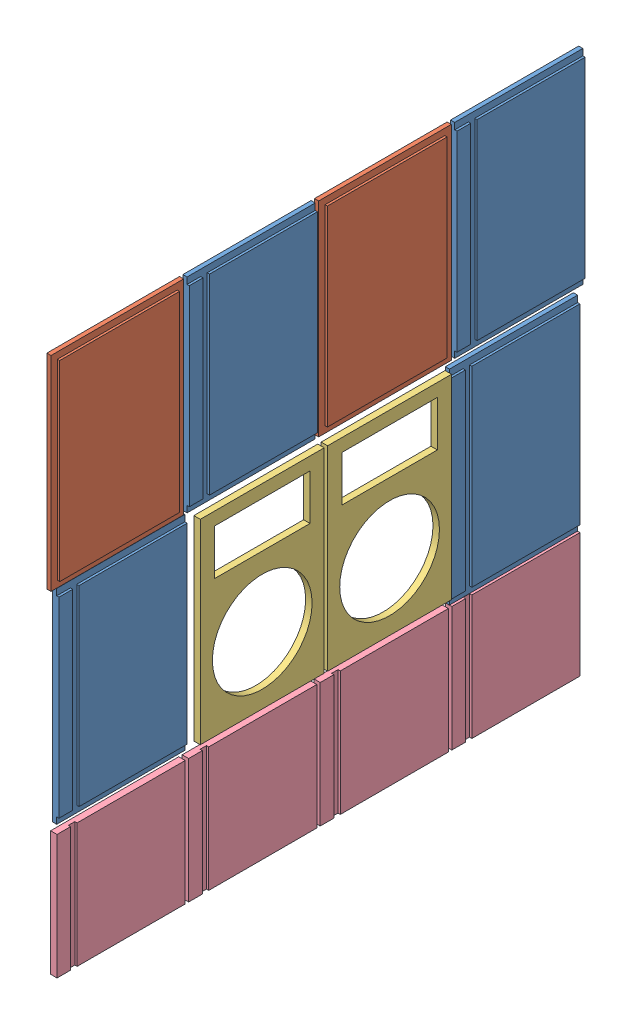
SolidWorks assembly 5x5sheet, configuration Default. Lengths in mm.
Overall size (45 1505.75 1483.58).
12 component instances, 4 part files, 29 mates.
Components (placement in the parent):
- side-1: side [Default] at (-587.3677 340.2677 830.6585) size (18 570 357.5)
- side-2: side [Default] at (-587.3677 340.2677 1577.2085) size (18 570 357.5)
- back-1: back [Default] at (-587.3677 340.2677 1210.1835) x (0 0 -1) z (1 0 0) size (370 570 18)
- Baffle-1: Baffle [Default] at (-551.3677 -213.8573 863.8532) x (0 0 1) z (-1 0 0) size (345.7 544.6 18)
- top_bottom-1: top_bottom [Default] at (-587.3677 -248.7823 1588.7649) x (0 -1 0) z (0 0 1) size (346.7 18 357.5)
- top_bottom-2: top_bottom [Default] at (-587.3677 -248.7823 487.6899) x (0 -1 0) z (0 0 1) size (346.7 18 357.5)
- back-2: back [Default] at (-587.3677 340.2677 1956.7335) x (0 0 -1) z (1 0 0) size (370 570 18)
- Baffle-2: Baffle [Default] at (-569.3677 -213.8573 1564.7782) x (0 0 -1) z (1 0 0) size (345.7 544.6 18)
- side-3: side [Default] at (-596.3677 -239.2573 1931.8032) size (18 570 357.5)
- side-4: side [Default] at (-578.3677 -239.2573 854.3282) size (18 570 357.5)
- top_bottom-3: top_bottom [Default] at (-587.3677 -248.7823 854.7149) x (0 -1 0) z (0 0 1) size (346.7 18 357.5)
- top_bottom-4: top_bottom [Default] at (-587.3677 -248.7823 1221.7399) x (0 -1 0) z (0 0 1) size (346.7 18 357.5)
Mates (geometry in assembly coordinates):
- Coincident1: coincident anti-aligned: plane of side-2 through (-569.3677 340.2677 1577.2085) normal (1 0 0); plane of Baffle-1 through (-569.3677 -213.8573 863.8532) normal (-1 0 0)
- Coincident2: coincident aligned: plane of side-1 through (-569.3677 340.2677 830.6585) normal (1 0 0); plane of side-2 through (-569.3677 340.2677 1577.2085) normal (1 0 0)
- Coincident3: coincident aligned: plane of side-1 through (-569.3677 340.2677 830.6585) normal (1 0 0); plane of back-1 through (-569.3677 340.2677 1210.1835) normal (1 0 0)
- Coincident4: coincident aligned: plane of side-1 through (-569.3677 340.2677 830.6585) normal (1 0 0); plane of top_bottom-2 through (-569.3677 -248.7823 487.6899) normal (1 0 0)
- Coincident5: coincident aligned: plane of top_bottom-1 through (-569.3677 -248.7823 1588.7649) normal (1 0 0); plane of top_bottom-2 through (-569.3677 -248.7823 487.6899) normal (1 0 0)
- Coincident6: coincident aligned: plane of back-1 through (-569.3677 340.2677 1210.1835) normal (1 0 0); plane of back-2 through (-569.3677 340.2677 1956.7335) normal (1 0 0)
- Coincident7: coincident aligned: plane of Baffle-1 through (-551.3677 -213.8573 863.8532) normal (1 0 0); plane of Baffle-2 through (-551.3677 -213.8573 1564.7782) normal (1 0 0)
- Coincident8: coincident aligned: plane of top_bottom-1 through (-569.3677 -248.7823 1588.7649) normal (1 0 0); plane of top_bottom-3 through (-569.3677 -248.7823 854.7149) normal (1 0 0)
- Coincident9: coincident aligned: plane of top_bottom-2 through (-569.3677 -248.7823 487.6899) normal (1 0 0); plane of top_bottom-4 through (-569.3677 -248.7823 1221.7399) normal (1 0 0)
- Coincident10: coincident aligned: plane of side-2 through (-569.3677 910.2677 1577.2085) normal (0 1 0); plane of back-2 through (-569.3677 910.2677 1956.7335) normal (0 1 0)
- Coincident11: coincident aligned: plane of side-2 through (-569.3677 910.2677 1577.2085) normal (0 1 0); plane of back-1 through (-569.3677 910.2677 1210.1835) normal (0 1 0)
- Coincident12: coincident aligned: plane of side-1 through (-569.3677 910.2677 830.6585) normal (0 1 0); plane of back-1 through (-569.3677 910.2677 1210.1835) normal (0 1 0)
- Coincident13: coincident aligned: plane of top_bottom-1 through (-569.3677 -595.4823 1588.7649) normal (0 -1 0); plane of top_bottom-4 through (-569.3677 -595.4823 1221.7399) normal (0 -1 0)
- Coincident14: coincident aligned: plane of top_bottom-3 through (-569.3677 -595.4823 854.7149) normal (0 -1 0); plane of top_bottom-4 through (-569.3677 -595.4823 1221.7399) normal (0 -1 0)
- Coincident15: coincident aligned: plane of top_bottom-2 through (-569.3677 -595.4823 487.6899) normal (0 -1 0); plane of top_bottom-3 through (-569.3677 -595.4823 854.7149) normal (0 -1 0)
- Distance1: distance = 9.525 mm anti-aligned: plane of Baffle-2 through (-551.3677 -213.8573 1564.7782) normal (0 0 1); plane of side-3 through (-578.3677 -239.2573 1574.3032) normal (0 0 -1)
- Distance2: distance = 9.525 mm anti-aligned: plane of Baffle-1 through (-569.3677 -213.8573 1209.5532) normal (0 0 1); plane of Baffle-2 through (-551.3677 -213.8573 1219.0782) normal (0 0 -1)
- Distance3: distance = 9.525 mm anti-aligned: plane of side-4 through (-560.3677 -239.2573 854.3282) normal (0 0 1); plane of Baffle-1 through (-569.3677 -213.8573 863.8532) normal (0 0 -1)
- Distance4: distance = 9.525 mm anti-aligned: plane of side-2 through (-569.3677 340.2677 1577.2085) normal (0 0 1); plane of back-2 through (-569.3677 340.2677 1586.7335) normal (0 0 -1)
- Distance5: distance = 9.525 mm anti-aligned: plane of side-2 through (-569.3677 340.2677 1219.7085) normal (0 0 -1); plane of back-1 through (-569.3677 340.2677 1210.1835) normal (0 0 1)
- Distance6: distance = 9.525 mm anti-aligned: plane of side-1 through (-569.3677 340.2677 830.6585) normal (0 0 1); plane of back-1 through (-569.3677 340.2677 840.1835) normal (0 0 -1)
- Distance7: distance = 9.525 mm anti-aligned: plane of back-2 through (-569.3677 340.2677 1956.7335) normal (0 -1 0); plane of side-3 through (-578.3677 330.7427 1931.8032) normal (0 1 0)
- Distance8: distance = 9.525 mm anti-aligned: plane of Baffle-2 through (-551.3677 330.7427 1564.7782) normal (0 1 0); plane of side-2 through (-569.3677 340.2677 1577.2085) normal (0 -1 0)
- Distance9: distance = 9.525 mm anti-aligned: plane of back-1 through (-569.3677 340.2677 1210.1835) normal (0 -1 0); plane of Baffle-1 through (-569.3677 330.7427 863.8532) normal (0 1 0)
- Distance10: distance = 9.525 mm anti-aligned: plane of side-4 through (-560.3677 330.7427 854.3282) normal (0 1 0); plane of side-1 through (-569.3677 340.2677 830.6585) normal (0 -1 0)
- Distance11: distance = 9.525 mm anti-aligned: plane of top_bottom-1 through (-569.3677 -248.7823 1588.7649) normal (0 1 0); plane of side-3 through (-578.3677 -239.2573 1931.8032) normal (0 -1 0)
- Distance12: distance = 9.525 mm anti-aligned: plane of top_bottom-4 through (-569.3677 -248.7823 1579.2399) normal (0 0 1); plane of top_bottom-1 through (-569.3677 -248.7823 1588.7649) normal (0 0 -1)
- Distance13: distance = 9.525 mm anti-aligned: plane of top_bottom-4 through (-569.3677 -248.7823 1221.7399) normal (0 0 -1); plane of top_bottom-3 through (-569.3677 -248.7823 1212.2149) normal (0 0 1)
- Distance14: distance = 9.525 mm anti-aligned: plane of top_bottom-2 through (-569.3677 -248.7823 845.1899) normal (0 0 1); plane of top_bottom-3 through (-569.3677 -248.7823 854.7149) normal (0 0 -1)
